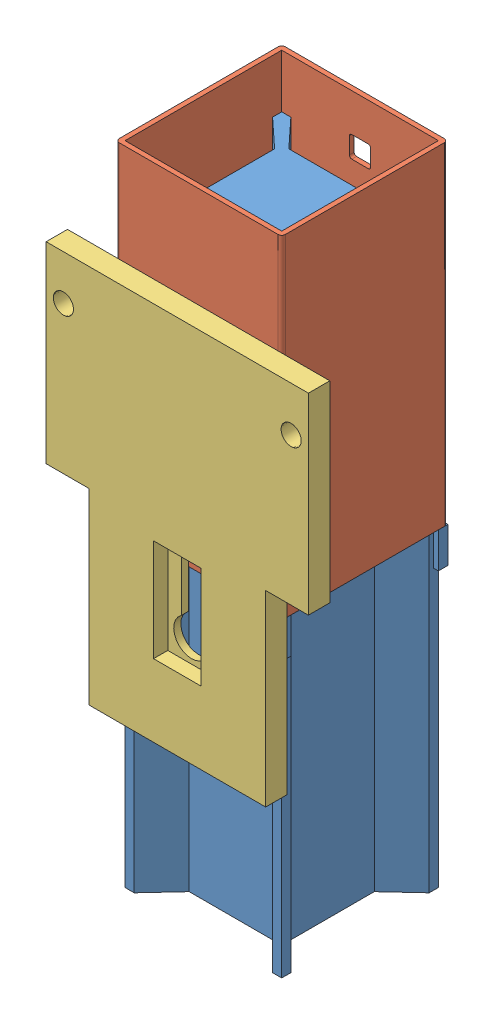
SolidWorks assembly B40-5F--2, configuration Default. Lengths in mm.
Overall size (110.5 272.5 79).
3 component instances, 3 part files, 0 mates.
Components (placement in the parent):
- B00-042-KR--1: B00-042-KR- [Default] at origin size (70 250 70)
- G2284--1: G2284- [Default] at (0 77.5 0) x (0 0 -1) z (1 0 0) size (70 140 70)
- Rail_Plate--1: Rail_Plate- [Default] at (0 -55 35) size (110.5 160 9)
